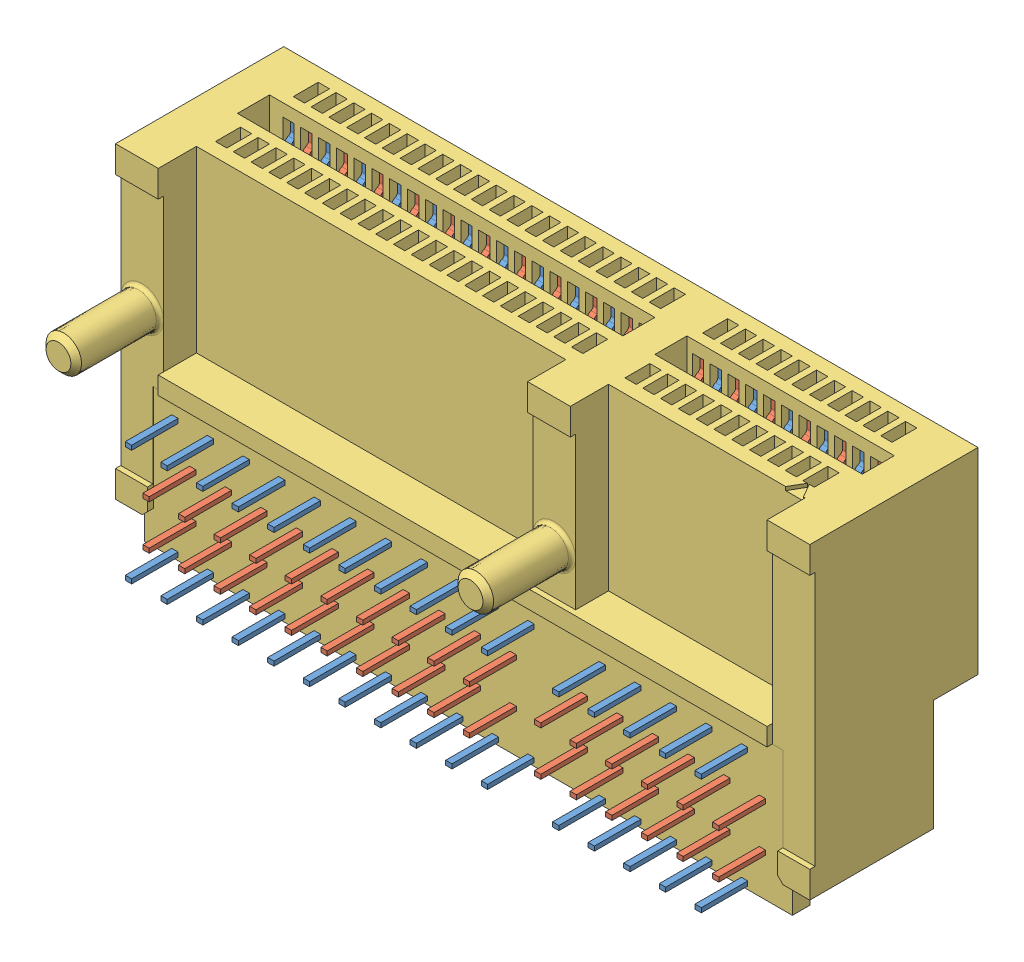
SolidWorks assembly PCIE-064-02-X-D-RA, configuration Default. Lengths in mm.
Overall size (39 18.85 13.86).
4 component instances, 3 part files, 0 mates.
Components (placement in the parent):
- PCIE-064-02-X-D-RA.step-1: PCIE-064-02-X-D-RA.step [Default] at origin size (39 18.85 13.86)
  - PCIE-064-02-F-D-RA_pins2.step-1: PCIE-064-02-F-D-RA_pins2.step [Default] at (6.9945 0 0) size (34 17.93 10.46)
  - PCIE-064-02-F-D-RA_pins1.step-1: PCIE-064-02-F-D-RA_pins1.step [Default] at (6.9945 0 0) size (34 16.93 10.47)
  - PCIE-064-02-F-D-RA_body.step-1: PCIE-064-02-F-D-RA_body.step [Default] at origin size (39 18.85 13.86)
